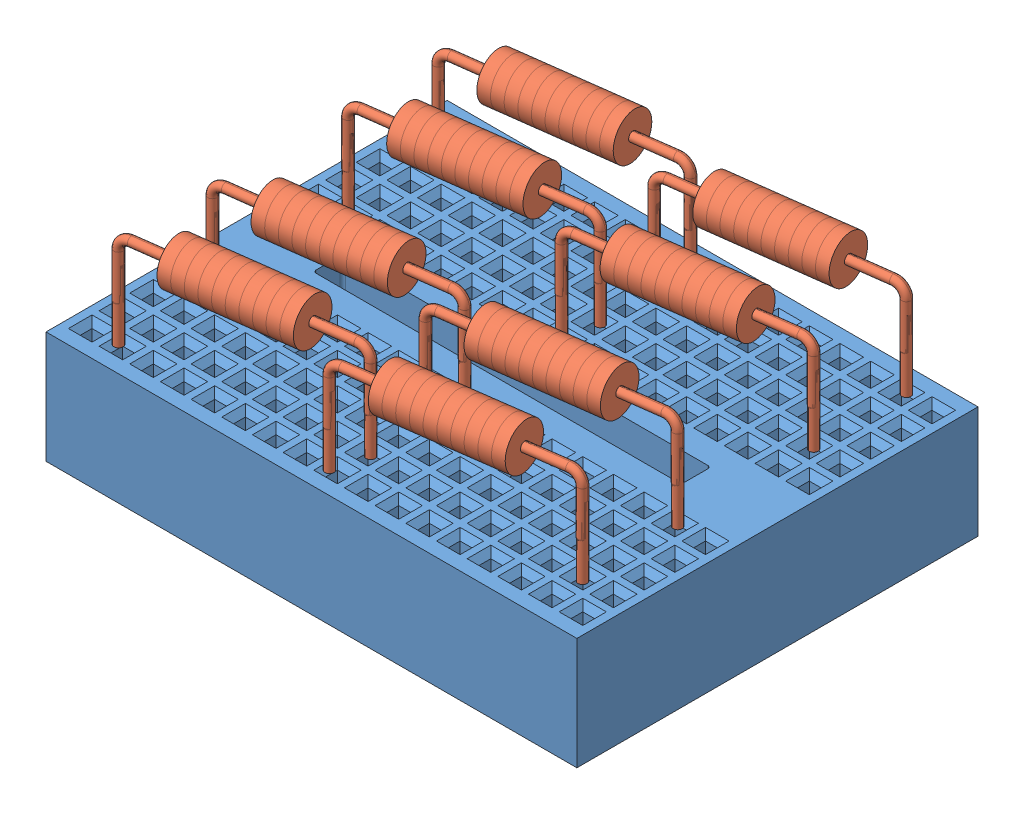
SolidWorks assembly Protoboard_with_resistors, configuration Default. Lengths in mm.
Overall size (45 19.41 34.07).
9 component instances, 2 part files, 8 mates.
Components (placement in the parent):
- MINIPROTOBOARD-1: MINIPROTOBOARD [Default] at (20.7748 18.9712 36.8488) size (45 9.5 34)
- Resistor Carbon Film 0W5 L10.3 D3.8 LD0.77mm Horizontal-1: Resistor Carbon Film 0W5 L10.3 D3.8 LD0.77mm Horizontal [Default] at (29.8566 34.4712 50.6841) x (0.990749 0 -0.135704) z (0 1 0) size (19.83 3.81 9.91)
- Resistor Carbon Film 0W5 L10.3 D3.8 LD0.77mm Horizontal-2: Resistor Carbon Film 0W5 L10.3 D3.8 LD0.77mm Horizontal [Default] at (29.9349 34.4712 31.1282) x (0.991455 0 -0.130446) z (0 1 0) size (19.83 3.81 9.91)
- Resistor Carbon Film 0W5 L10.3 D3.8 LD0.77mm Horizontal-3: Resistor Carbon Film 0W5 L10.3 D3.8 LD0.77mm Horizontal [Default] at (29.8373 34.4712 23.175) x (0.991455 0 -0.130446) z (0 1 0) size (19.83 3.81 9.91)
- Resistor Carbon Film 0W5 L10.3 D3.8 LD0.77mm Horizontal-4: Resistor Carbon Film 0W5 L10.3 D3.8 LD0.77mm Horizontal [Default] at (11.6938 34.4712 50.4431) x (0.991455 0 -0.130446) z (0 1 0) size (19.83 3.81 9.91)
- Resistor Carbon Film 0W5 L10.3 D3.8 LD0.77mm Horizontal-5: Resistor Carbon Film 0W5 L10.3 D3.8 LD0.77mm Horizontal [Default] at (11.7515 34.4712 42.5299) x (0.991455 0 -0.130446) z (0 1 0) size (19.83 3.81 9.91)
- Resistor Carbon Film 0W5 L10.3 D3.8 LD0.77mm Horizontal-6: Resistor Carbon Film 0W5 L10.3 D3.8 LD0.77mm Horizontal [Default] at (11.7518 34.4712 31.0334) x (0.991455 0 -0.130446) z (0 1 0) size (19.83 3.81 9.91)
- Resistor Carbon Film 0W5 L10.3 D3.8 LD0.77mm Horizontal-7: Resistor Carbon Film 0W5 L10.3 D3.8 LD0.77mm Horizontal [Default] at (29.8542 34.4712 42.577) x (0.991455 0 -0.130446) z (0 1 0) size (19.83 3.81 9.91)
- Resistor Carbon Film 0W5 L10.3 D3.8 LD0.77mm Horizontal-8: Resistor Carbon Film 0W5 L10.3 D3.8 LD0.77mm Horizontal [Default] at (11.664 34.4712 23.3005) x (0.991455 0 -0.130446) z (0 1 0) size (19.83 3.81 9.91)
Mates (geometry in assembly coordinates):
- Coincident1: coincident anti-aligned: plane of MINIPROTOBOARD-1 through (20.7748 28.4712 36.8488) normal (0 1 0); plane of Resistor Carbon Film 0W5 L10.3 D3.8 LD0.77mm Horizontal-8 through (2.2274 28.4712 24.5421) normal (0 -1 0)
- Coincident2: coincident anti-aligned: plane of MINIPROTOBOARD-1 through (20.7748 28.4712 36.8488) normal (0 1 0); plane of Resistor Carbon Film 0W5 L10.3 D3.8 LD0.77mm Horizontal-6 through (2.3153 28.4712 32.275) normal (0 -1 0)
- Coincident3: coincident anti-aligned: plane of MINIPROTOBOARD-1 through (20.7748 28.4712 36.8488) normal (0 1 0); plane of Resistor Carbon Film 0W5 L10.3 D3.8 LD0.77mm Horizontal-5 through (2.3149 28.4712 43.7714) normal (0 -1 0)
- Coincident4: coincident anti-aligned: plane of MINIPROTOBOARD-1 through (20.7748 28.4712 36.8488) normal (0 1 0); plane of Resistor Carbon Film 0W5 L10.3 D3.8 LD0.77mm Horizontal-4 through (2.2572 28.4712 51.6847) normal (0 -1 0)
- Coincident5: coincident anti-aligned: plane of MINIPROTOBOARD-1 through (20.7748 28.4712 36.8488) normal (0 1 0); plane of Resistor Carbon Film 0W5 L10.3 D3.8 LD0.77mm Horizontal-3 through (39.288 28.4712 21.9315) normal (0 -1 0)
- Coincident6: coincident anti-aligned: plane of MINIPROTOBOARD-1 through (20.7748 28.4712 36.8488) normal (0 1 0); plane of Resistor Carbon Film 0W5 L10.3 D3.8 LD0.77mm Horizontal-2 through (39.3856 28.4712 29.8848) normal (0 -1 0)
- Coincident7: coincident aligned: plane of MINIPROTOBOARD-1 through (20.7748 28.4712 36.8488) normal (0 1 0); circle of Resistor Carbon Film 0W5 L10.3 D3.8 LD0.77mm Horizontal-1
- Coincident8: coincident anti-aligned: plane of MINIPROTOBOARD-1 through (20.7748 28.4712 36.8488) normal (0 1 0); plane of Resistor Carbon Film 0W5 L10.3 D3.8 LD0.77mm Horizontal-7 through (39.3049 28.4712 41.3336) normal (0 -1 0)
